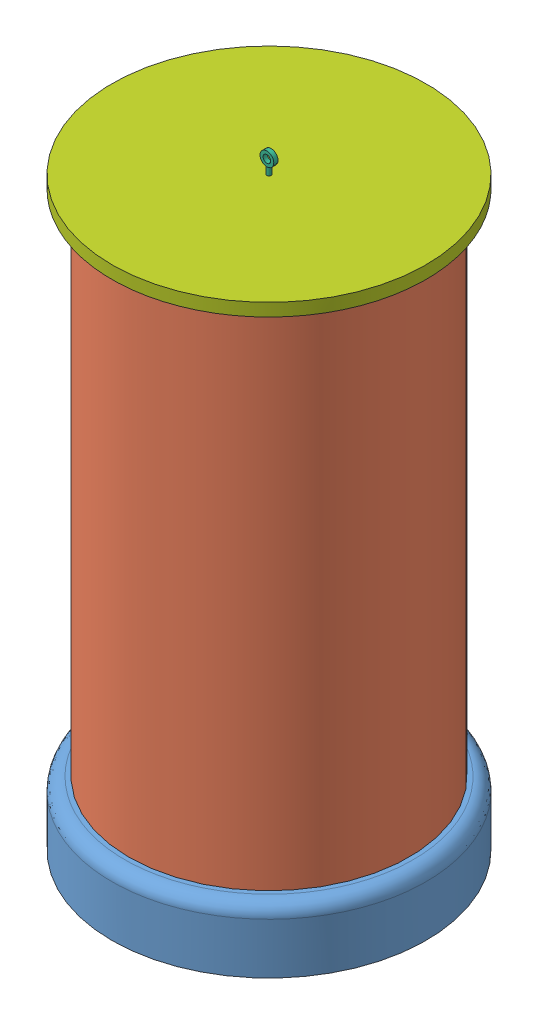
SolidWorks assembly Assem1, configuration Default. Lengths in mm.
Overall size (99.33 142.9 99.33).
11 component instances, 7 part files, 25 mates.
Components (placement in the parent):
- base-1: base [Default] at (28.106 18.1593 74.1815) size (74 19 74)
- body-1: body [Default] at (28.106 18.1593 74.1815) size (66 120 66)
- pcb-1: pcb [Default] at (28.106 75.4879 74.1815) x (0 0 -1) z (1 0 0) size (54.94 4 54.94)
- pcb top-1: pcb top [Default] at (28.106 108.5441 74.1815) size (54.94 4 54.94)
- rod-1: rod [Default] at (4.135 12.5441 74.1815) size (4.61 103 4.13)
- ROD2-1: ROD2 [Default] at (28.106 108.5441 74.1815) size (3.25 37.51 1)
- top-1: top [Default] at (28.106 138.6593 74.1815) x (0.448522 0 -0.893772) z (0 -1 0) size (74 74 8.75)
- rod-2: rod [Default] at (28.106 12.5441 98.1525) size (4.61 103 4.13)
- rod-3: rod [Default] at (52.077 12.5441 74.1815) size (4.61 103 4.13)
- rod-4: rod [Default] at (28.106 12.5441 50.2105) size (4.61 103 4.13)
- pcb-2: pcb [Default] at (28.106 37.8656 74.1815) x (-1 0 0) z (0 0 -1) size (54.94 4 54.94)
Mates (geometry in assembly coordinates):
- Concentric2: concentric anti-aligned: cylinder of pcb top-1 through (28.106 108.5441 50.2105) axis (0 1 0) radius 2; cylinder of rod-4 through (28.106 112.5441 50.2105) axis (0 -1 0) radius 1.5
- Concentric3: concentric anti-aligned: cylinder of pcb top-1 through (4.135 108.5441 74.1815) axis (0 1 0) radius 2; cylinder of rod-1 through (4.135 112.5441 74.1815) axis (0 -1 0) radius 1.5
- Concentric4: concentric anti-aligned: cylinder of pcb top-1 through (28.106 108.5441 98.1525) axis (0 1 0) radius 2; cylinder of rod-2 through (28.106 112.5441 98.1525) axis (0 -1 0) radius 1.5
- Concentric5: concentric anti-aligned: cylinder of pcb top-1 through (52.077 108.5441 74.1815) axis (0 1 0) radius 2; cylinder of rod-3 through (52.077 112.5441 74.1815) axis (0 -1 0) radius 1.5
- Coincident1: coincident anti-aligned: plane of pcb top-1 through (28.106 112.5441 74.1815) normal (0 1 0); plane of rod-1 through (4.135 112.5441 74.1815) normal (0 -1 0)
- Coincident3: coincident anti-aligned: plane of pcb top-1 through (28.106 112.5441 74.1815) normal (0 1 0); plane of rod-4 through (28.106 112.5441 50.2105) normal (0 -1 0)
- Coincident4: coincident anti-aligned: plane of pcb top-1 through (28.106 112.5441 74.1815) normal (0 1 0); plane of rod-2 through (28.106 112.5441 98.1525) normal (0 -1 0)
- Coincident5: coincident anti-aligned: plane of pcb top-1 through (28.106 112.5441 74.1815) normal (0 1 0); plane of rod-3 through (52.077 112.5441 74.1815) normal (0 -1 0)
- Concentric6: concentric anti-aligned: cylinder of pcb-1 through (28.106 75.4879 98.1525) axis (0 1 0) radius 2; cylinder of rod-2 through (28.106 112.5441 98.1525) axis (0 -1 0) radius 1.5
- Concentric7: concentric anti-aligned: cylinder of pcb-1 through (52.077 75.4879 74.1815) axis (0 1 0) radius 2; cylinder of rod-3 through (52.077 112.5441 74.1815) axis (0 -1 0) radius 1.5
- Concentric8: concentric anti-aligned: cylinder of pcb top-1 through (28.106 108.5441 74.1815) axis (0 1 0) radius 0.5; cylinder of ROD2-1 through (28.106 143.5441 74.1815) axis (0 -1 0) radius 0.5
- Coincident6: coincident aligned: circle of pcb top-1; circle of ROD2-1
- Concentric9: concentric anti-aligned: cylinder of ROD2-1 through (28.106 143.5441 74.1815) axis (0 -1 0) radius 0.5; cylinder of top-1 through (28.106 132.3197 74.1815) axis (0 1 0) radius 0.5
- Concentric10: concentric anti-aligned: cylinder of base-1 through (52.077 18.1593 74.1815) axis (0 1 0) radius 2; cylinder of rod-3 through (52.077 112.5441 74.1815) axis (0 -1 0) radius 1.5
- Concentric11: concentric anti-aligned: cylinder of base-1 through (28.106 18.1593 98.1525) axis (0 1 0) radius 2; cylinder of rod-2 through (28.106 112.5441 98.1525) axis (0 -1 0) radius 1.5
- Coincident7: coincident anti-aligned: plane of body-1 through (28.106 138.1593 74.1815) normal (0 1 0); plane of top-1 through (28.106 138.1593 74.1815) normal (0 -1 0)
- Concentric12: concentric anti-aligned: cylinder of rod-4 through (28.106 112.5441 50.2105) axis (0 -1 0) radius 1.5; cylinder of pcb-2 through (28.106 37.8656 50.2105) axis (0 1 0) radius 2
- Concentric14: concentric anti-aligned: cylinder of rod-1 through (4.135 112.5441 74.1815) axis (0 -1 0) radius 1.5; cylinder of pcb-2 through (4.135 37.8656 74.1815) axis (0 1 0) radius 2
- Concentric15: concentric anti-aligned: cylinder of base-1 through (52.077 18.1593 74.1815) axis (0 1 0) radius 2; cylinder of rod-3 through (52.077 112.5441 74.1815) axis (0 -1 0) radius 1.5
- Concentric16: concentric anti-aligned: cylinder of base-1 through (28.106 18.1593 50.2105) axis (0 1 0) radius 2; cylinder of rod-4 through (28.106 112.5441 50.2105) axis (0 -1 0) radius 1.5
- Parallel1: parallel anti-aligned: cylinder of base-1 through (28.106 18.1593 50.2105) axis (0 1 0) radius 2; cylinder of rod-1 through (4.135 112.5441 74.1815) axis (0 -1 0) radius 1.5
- Concentric18: concentric aligned: circle of base-1; circle of rod-1
- Concentric19: concentric anti-aligned: circle of base-1; cylinder of rod-1 through (4.135 112.5441 74.1815) axis (0 -1 0) radius 1.5
- Coincident9: coincident anti-aligned: plane of base-1 through (28.106 18.1593 74.1815) normal (0 1 0); plane of body-1 through (28.106 18.1593 74.1815) normal (0 -1 0)
- Concentric20: concentric aligned: circle of base-1; circle of body-1
